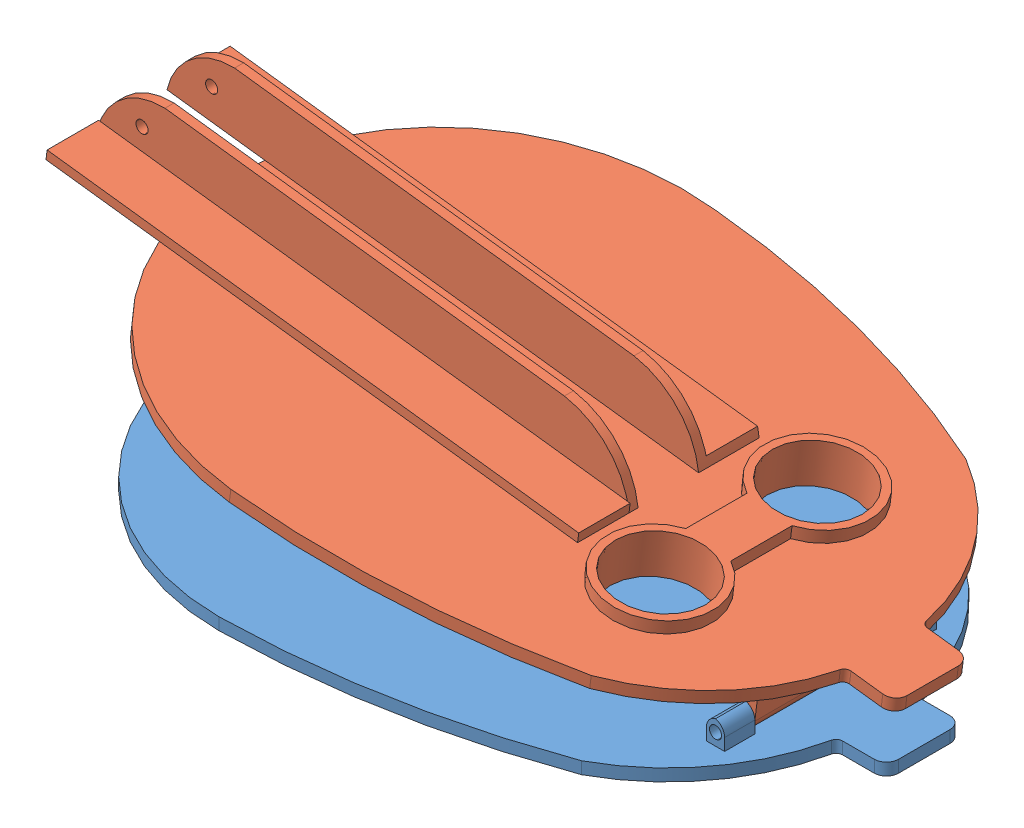
SolidWorks assembly fuelle, configuration Default. Lengths in mm.
Overall size (268.39 76.17 160.08).
2 component instances, 2 part files, 2 mates.
Components (placement in the parent):
- tapa de fuelle-1: tapa de fuelle [Default] at (10.9116 -25.901 -0.6972) size (233.07 11.87 160.08)
- tapa sup de fuelle-1: tapa sup de fuelle [Default] at (14.1346 9.1106 -0.6972) x (0.992398 -0.123072 0) z (0 0 1) size (265 43.89 160.08)
Mates (geometry in assembly coordinates):
- Concentric1: concentric: cylinder of tapa de fuelle-1 through (101.939 -17.901 54.3028) axis (0 0 -1) radius 2; cylinder of tapa sup de fuelle-1 through (101.939 -17.901 -34.6972) axis (0 0 1) radius 2
- Coincident1: coincident: plane of tapa de fuelle-1 through (98.939 -13.901 24.3028) normal (0 0 -1); plane of tapa sup de fuelle-1 through (98.4695 -21.5014 24.3028) normal (0 0 1)
